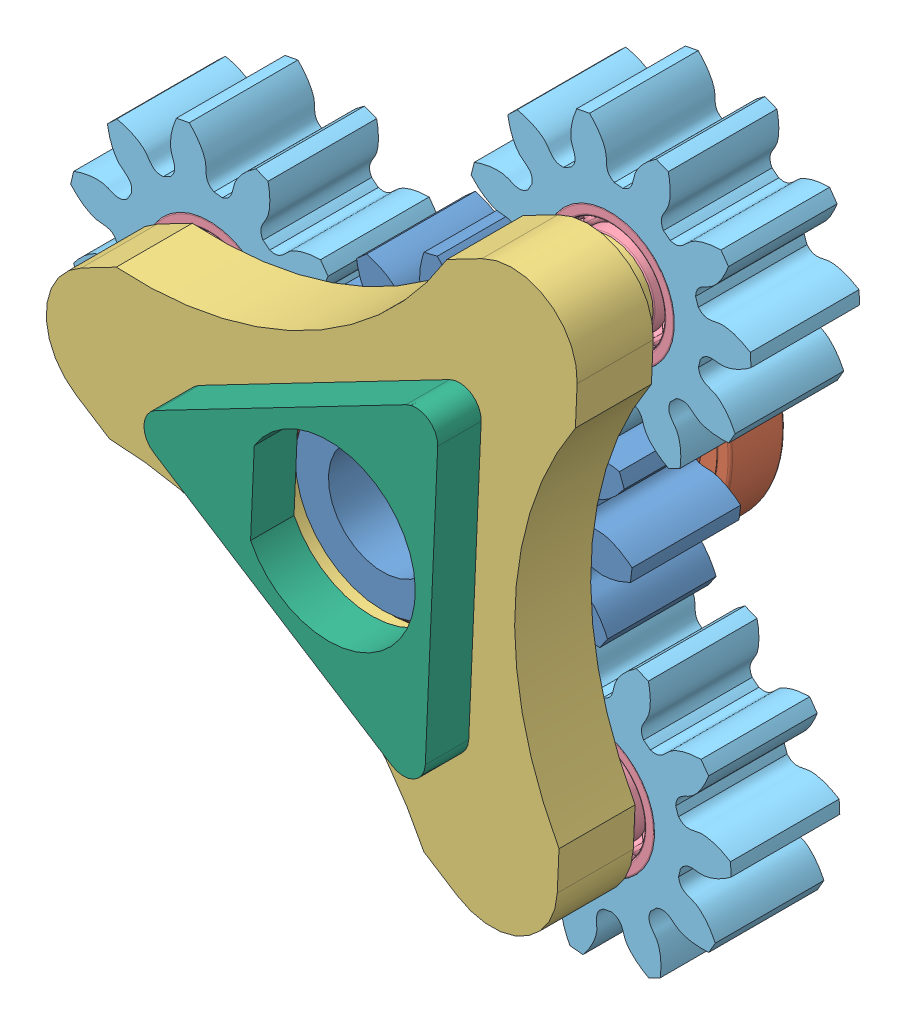
SolidWorks assembly Reducer_PanetGearTrains1, configuration Default. Lengths in mm.
Overall size (39.43 38.65 16.5).
11 component instances, 6 part files, 24 mates.
Components (placement in the parent):
- Reducer_PGT_SunGear1-1: Reducer_PGT_SunGear1 [默认] at origin size (14.95 14.85 14)
- GB╱T 276-2013[617╱8-2Z]-1: GB╱T 276-2013[617╱8-2Z] [617╱8-2Z] at (0 0 7.25) x (0 0 -1) z (0.846583 0.532257 0) size (2.5 12 12)
- GB╱T 276-2013[617╱8-2Z]-2: GB╱T 276-2013[617╱8-2Z] [617╱8-2Z] at (0 0 -2.25) x (0 0 -1) z (0.991248 -0.132011 0) size (2.5 12 12)
- Reducer_PGT_PlanetCarrier-1: Reducer_PGT_PlanetCarrier [默认] at (0 0 8.5) x (0.887175 0.461432 0) z (0 0 -1) size (26.78 24 8.5)
- GB╱T 276-2013[617╱3]-2: GB╱T 276-2013[617╱3] [617╱3] at (5.5372 -10.6461 4) x (0 0 1) z (-1 0 0) size (2 6 6)
- GB╱T 276-2013[617╱3]-3: GB╱T 276-2013[617╱3] [617╱3] at (-11.9884 0.5277 4) x (0 0 1) z (-1 0 0) size (2 6 6)
- GB╱T 276-2013[617╱3]-4: GB╱T 276-2013[617╱3] [617╱3] at (6.4512 10.1184 4) x (0 0 1) z (-1 0 0) size (2 6 6)
- Reducer_PGT_PlanetGear-1: Reducer_PGT_PlanetGear [默认] at (5.5372 -10.6461 0) x (-0.235835 -0.971793 0) z (0 0 1) size (12.94 12.81 5)
- Reducer_PGT_PlanetGear-2: Reducer_PGT_PlanetGear [默认] at (6.4512 10.1184 0) x (-0.579759 0.814788 0) z (0 0 1) size (12.94 12.81 5)
- Reducer_PGT_PlanetGear-3: Reducer_PGT_PlanetGear [默认] at (-11.9884 0.5277 0) x (0.890082 0.4558 0) z (0 0 1) size (12.94 12.81 5)
- Reducer_PGT_Joint1-1: Reducer_PGT_Joint1 [默认] at (4.7454 -0.2089 11.5) x (-0.043975 -0.999033 0) z (0 0 -1) size (14.99 13.25 6)
Mates (geometry in assembly coordinates):
- 重合1: coincident anti-aligned: plane of Reducer_PGT_SunGear1-1 through (0 0 6) normal (0 0 1); plane of GB╱T 276-2013[617╱8-2Z]-1 through (-2.3656 3.7626 6) normal (0 0 -1)
- 同心1: concentric anti-aligned: cylinder of Reducer_PGT_SunGear1-1 through (0 0 9) axis (0 0 -1) radius 4.025; cylinder of GB╱T 276-2013[617╱8-2Z]-1 through (0 0 10.75) axis (0 0 1) radius 4
- 同心2: concentric anti-aligned: cylinder of Reducer_PGT_SunGear1-1 through (0 0 9) axis (0 0 -1) radius 4.025; cylinder of GB╱T 276-2013[617╱8-2Z]-2 through (0 0 1.25) axis (0 0 1) radius 4
- 重合2: coincident anti-aligned: plane of Reducer_PGT_SunGear1-1 through (0 0 -1) normal (0 0 -1); plane of GB╱T 276-2013[617╱8-2Z]-2 through (0.5412 4.0641 -1) normal (0 0 1)
- 同心3: concentric aligned: cylinder of GB╱T 276-2013[617╱8-2Z]-1 through (0 0 10.75) axis (0 0 1) radius 6; cylinder of Reducer_PGT_PlanetCarrier-1 through (0 0 -1.5) axis (0 0 1) radius 5.975
- 重合3: coincident anti-aligned: plane of GB╱T 276-2013[617╱8-2Z]-1 through (-3.1403 4.9948 8.5) normal (0 0 1); plane of Reducer_PGT_PlanetCarrier-1 through (6.4512 10.1184 8.5) normal (0 0 -1)
- 重合4: coincident anti-aligned: plane of Reducer_PGT_PlanetCarrier-1 through (5.5372 -10.6461 5) normal (0 0 -1); plane of GB╱T 276-2013[617╱3]-2 through (5.5372 -8.7261 5) normal (0 0 1)
- 同心6: concentric anti-aligned: cylinder of Reducer_PGT_PlanetCarrier-1 through (5.5372 -10.6461 1) axis (0 0 1) radius 1.525; cylinder of GB╱T 276-2013[617╱3]-2 through (5.5372 -10.6461 0.5) axis (0 0 -1) radius 1.5
- 重合5: coincident anti-aligned: plane of Reducer_PGT_PlanetCarrier-1 through (-11.9884 0.5277 5) normal (0 0 -1); plane of GB╱T 276-2013[617╱3]-3 through (-11.9884 2.4477 5) normal (0 0 1)
- 同心7: concentric anti-aligned: cylinder of Reducer_PGT_PlanetCarrier-1 through (-11.9884 0.5277 1) axis (0 0 1) radius 1.525; cylinder of GB╱T 276-2013[617╱3]-3 through (-11.9884 0.5277 0.5) axis (0 0 -1) radius 1.5
- 重合6: coincident anti-aligned: plane of Reducer_PGT_PlanetCarrier-1 through (6.4512 10.1184 5) normal (0 0 -1); plane of GB╱T 276-2013[617╱3]-4 through (6.4512 12.0384 5) normal (0 0 1)
- 同心8: concentric anti-aligned: cylinder of Reducer_PGT_PlanetCarrier-1 through (6.4512 10.1184 1) axis (0 0 1) radius 1.525; cylinder of GB╱T 276-2013[617╱3]-4 through (6.4512 10.1184 0.5) axis (0 0 -1) radius 1.5
- 同心9: concentric anti-aligned: cylinder of GB╱T 276-2013[617╱3]-2 through (5.5372 -10.6461 0.5) axis (0 0 -1) radius 3; cylinder of Reducer_PGT_PlanetGear-1 through (5.5372 -10.6461 -5) axis (0 0 1) radius 2.975
- 重合7: coincident aligned: plane of Reducer_PGT_SunGear1-1 through (0 0 0) normal (0 0 -1); plane of Reducer_PGT_PlanetGear-1 through (5.5372 -10.6461 0) normal (0 0 -1)
- 同心10: concentric anti-aligned: cylinder of GB╱T 276-2013[617╱3]-4 through (6.4512 10.1184 0.5) axis (0 0 -1) radius 3; cylinder of Reducer_PGT_PlanetGear-2 through (6.4512 10.1184 -5) axis (0 0 1) radius 2.975
- 重合8: coincident aligned: plane of Reducer_PGT_SunGear1-1 through (0 0 0) normal (0 0 -1); plane of Reducer_PGT_PlanetGear-2 through (6.4512 10.1184 0) normal (0 0 -1)
- 同心11: concentric anti-aligned: cylinder of GB╱T 276-2013[617╱3]-3 through (-11.9884 0.5277 0.5) axis (0 0 -1) radius 3; cylinder of Reducer_PGT_PlanetGear-3 through (-11.9884 0.5277 -5) axis (0 0 1) radius 2.975
- 重合9: coincident aligned: plane of Reducer_PGT_SunGear1-1 through (0 0 0) normal (0 0 -1); plane of Reducer_PGT_PlanetGear-3 through (-11.9884 0.5277 0) normal (0 0 -1)
- 齿轮配合2: gear = 13 : 11 mm: circle of Reducer_PGT_PlanetGear-1; circle of Reducer_PGT_SunGear1-1
- 齿轮配合3: gear = 11 : 13 mm: circle of Reducer_PGT_SunGear1-1; circle of Reducer_PGT_PlanetGear-3
- 齿轮配合6: gear = 11 : 13 mm: circle of Reducer_PGT_SunGear1-1; circle of Reducer_PGT_PlanetGear-2
- 重合11: coincident anti-aligned: plane of Reducer_PGT_PlanetCarrier-1 through (6.4512 10.1184 9.5) normal (0 0 1); plane of Reducer_PGT_Joint1-1 through (3.4607 -6.6538 9.5) normal (0 0 -1)
- 同心14: concentric anti-aligned: cylinder of Reducer_PGT_PlanetCarrier-1 through (-7.4927 0.3298 16) axis (0 0 -1) radius 1; cylinder of Reducer_PGT_Joint1-1 through (-7.4927 0.3298 9.5) axis (0 0 1) radius 1
- 同心15: concentric anti-aligned: cylinder of Reducer_PGT_PlanetCarrier-1 through (4.032 6.324 16) axis (0 0 -1) radius 1; cylinder of Reducer_PGT_Joint1-1 through (4.032 6.324 9.5) axis (0 0 1) radius 1
